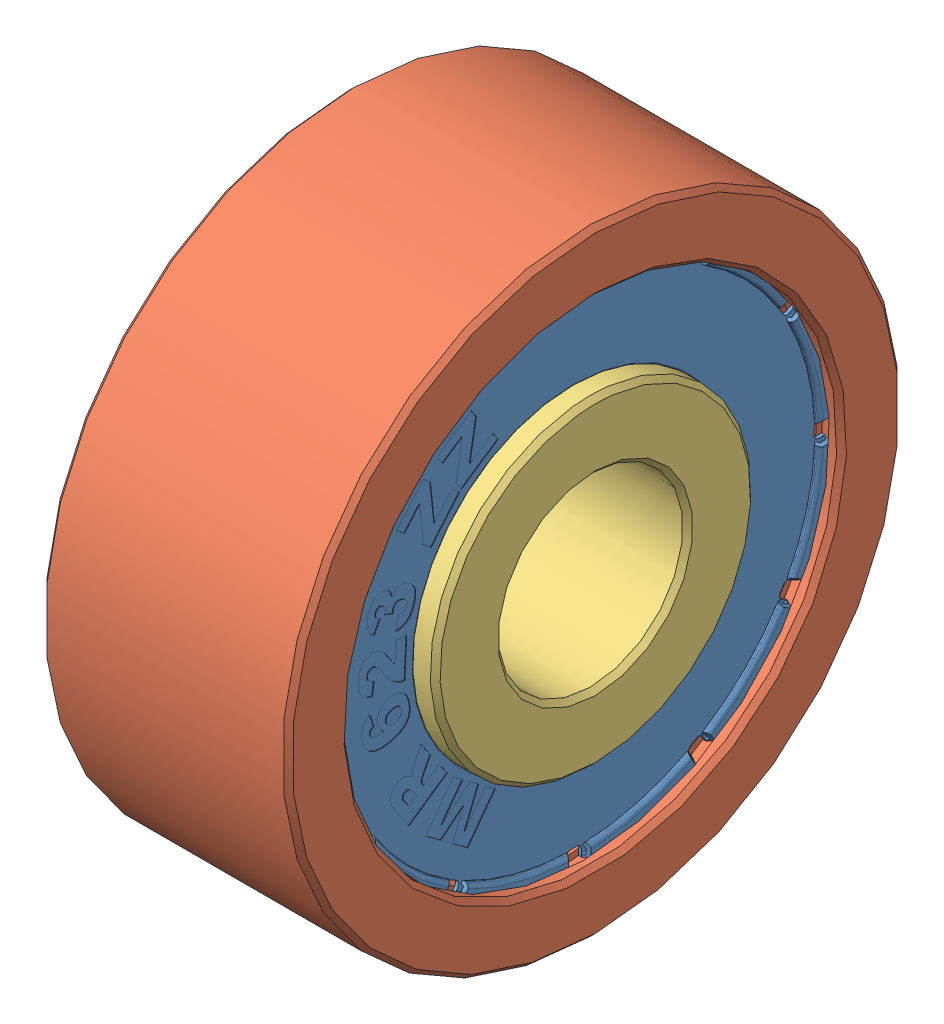
SolidWorks assembly -MR623ZZ-assem, configuration Default. Lengths in mm.
Overall size (4 10 10).
4 component instances, 3 part files, 6 mates.
Components (placement in the parent):
- mr623zz-cen-1: mr623zz-cen [Default] at (0.5 0 0) size (0.23 8.2 8.2)
- mr623zz-ext-1: mr623zz-ext [Default] at origin size (4 10 10)
- mr623zz-int-1: mr623zz-int [Default] at origin size (4 5.2 5.2)
- mr623zz-cen-2: mr623zz-cen [Default] at (-0.5 0 0) x (-1 0 0) z (0 0 1) size (0.23 8.2 8.2)
Mates (geometry in assembly coordinates):
- Coincident2: coincident: point of mr623zz-int-1
- Parallel1: parallel aligned: plane of mr623zz-int-1 through (2 -1.5 0) normal (1 0 0); plane of assembly through (0 0 0) normal (1 0 0)
- Coincident4: coincident anti-aligned: plane of mr623zz-cen-1 through (1.6 -2.65 0) normal (-1 0 0); plane of mr623zz-ext-1 through (1.6 -4 0) normal (1 0 0)
- Concentric1: concentric aligned: cylinder of mr623zz-cen-1 through (-5.929 0 0) axis (-1 0 0) radius 4.1; cylinder of mr623zz-ext-1 through (-6.429 0 0) axis (-1 0 0) radius 4.1
- Concentric2: concentric aligned: cylinder of mr623zz-ext-1 through (-6.429 0 0) axis (-1 0 0) radius 5; cylinder of mr623zz-int-1 through (-6.429 0 0) axis (-1 0 0) radius 1.5
- Coincident5: coincident aligned: plane of mr623zz-ext-1 through (2 -4 0) normal (1 0 0); plane of mr623zz-int-1 through (2 -1.5 0) normal (1 0 0)
